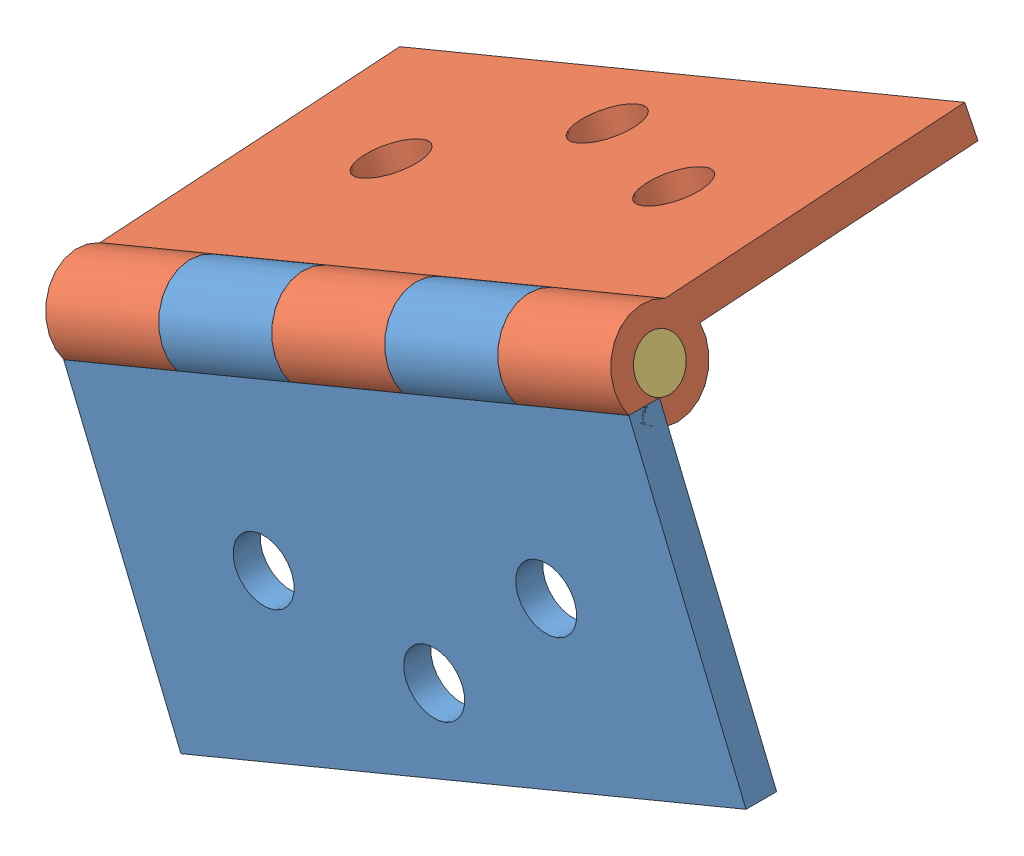
SolidWorks assembly Complete Hinge, configuration Default. Lengths in mm.
Overall size (116.85 97.34 61.91).
3 component instances, 3 part files, 6 mates.
Components (placement in the parent):
- Hinge 1-1: Hinge 1 [Default] at (227.1069 4.4476 137.0094) x (0.923728 0.383049 0) z (0 0 1) size (100 61.24 15)
- Hinge 2-1: Hinge 2 [Default] at (214.9756 33.7026 106.878) x (-0.923728 -0.383049 0) z (-0.382574 0.922583 0.049778) size (100 61.24 15)
- Hinge screw-1: Hinge screw [Default] at (168.7892 14.5501 106.878) x (0.382574 -0.922583 -0.049778) z (-0.923728 -0.383049 0) size (8.06 8.06 100)
Mates (geometry in assembly coordinates):
- Concentrico5: concentric anti-aligned: circle of Hinge 1-1; circle of Hinge 2-1
- Coincidente10: coincident anti-aligned: plane of Hinge 1-1 through (243.8093 42.4886 135.5094) normal (0.923728 0.383049 0); plane of Hinge 2-1 through (243.8093 42.4886 135.5094) normal (-0.923728 -0.383049 0)
- SulPosto1: in place: plane of ? through (171.3602 8.3501 129.0334) normal (-0.923728 -0.383049 0); plane of ? through (149.1716 61.8581 0) normal (-0.923728 -0.383049 0); moOrthogonalPlaneRef_w of ? through (171.3602 8.3501 129.0334) normal (-0.923728 -0.383049 0); plane of ? through (149.1716 61.8581 0) normal (-0.383049 0.923728 0); plane of ? through (171.3602 8.3501 129.0334) normal (-0.923728 -0.383049 0); plane of ? through (149.1716 61.8581 0) normal (0 0 1); plane of Hinge 2-1 through (167.353 18.0135 132.0959) normal (-0.923728 -0.383049 0); unknown of Hinge screw-1
- Coincidente11: coincident aligned: plane of ?; plane of ?
- Coincidente12: coincident aligned: moOrthogonalPlaneRef_w of Hinge 2-1; plane of Parte1^Complete Hinge-1 through (168.7892 14.5501 106.878) normal (0.019068 -0.045982 0.99876)
- Coincidente13: coincident anti-aligned: moOrthogonalPlaneRef_w of Hinge 2-1; plane of Parte1^Complete Hinge-1 through (168.7892 14.5501 106.878) normal (0.382574 -0.922583 -0.049778)
